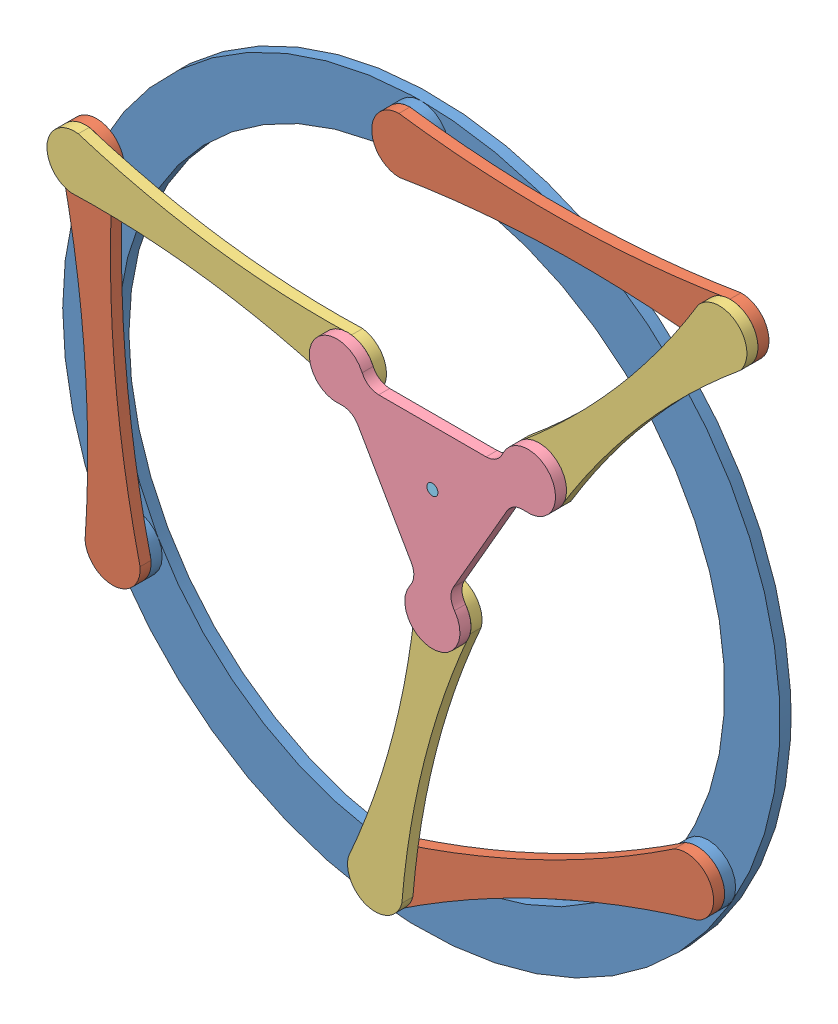
SolidWorks assembly 3RRR, configuration Default. Lengths in mm.
Overall size (660.23 664.5 50).
9 component instances, 5 part files, 21 mates.
Components (placement in the parent):
- Base-1: Base [Default] at origin size (650 650 20)
- Proximal Link-1: Proximal Link [Default] at (-272.0437 -0.4999 20) x (-0.081574 0.996667 0) z (0 0 1) size (350 50 20)
- Proximal Link-2: Proximal Link [Default] at (123.963 -213.6101 20) x (-0.905631 -0.424068 0) z (0 0 1) size (350 50 20)
- Proximal Link-3: Proximal Link [Default] at (149.985 302.119 20) x (0.9999 0.014127 0) z (0 0 1) size (350 50 20)
- Distal Link-1: Distal Link [Default] at (-160.4411 132.0001 30) x (0.990709 -0.136001 0) z (0 0 1) size (300 50 20)
- Distal Link-2: Distal Link [Default] at (19.0592 -156.1101 30) x (0.247526 0.968881 0) z (0 0 1) size (300 50 20)
- Distal Link-3: Distal Link [Default] at (218.2863 209.619 30) x (-0.65347 -0.756952 0) z (0 0 1) size (300 50 20)
- Platform-1: Platform [Default] at (50 65 50) x (-1 0 0) z (0 0 1) size (223.21 200 20)
- Pen-1: Pen [Default] at (50 65 50) x (0.104755 0.994498 0) z (0 0 -1) size (10 10 50)
Mates (geometry in assembly coordinates):
- Coincident5: coordinate: unknown of Base-1
- Concentric1: concentric anti-aligned: cylinder of Base-1 through (-259.8076 -150 20) axis (0 0 -1) radius 16.25; cylinder of Proximal Link-1 through (-259.8076 -150 10) axis (0 0 1) radius 16.25
- Coincident6: coincident anti-aligned: plane of Base-1 through (0 0 10) normal (0 0 1); plane of Proximal Link-1 through (-259.8076 -150 10) normal (0 0 -1)
- Concentric2: concentric anti-aligned: cylinder of Base-1 through (259.8076 -150 20) axis (0 0 -1) radius 16.25; cylinder of Proximal Link-2 through (259.8076 -150 10) axis (0 0 1) radius 16.25
- Coincident7: coincident anti-aligned: plane of Base-1 through (0 0 10) normal (0 0 1); plane of Proximal Link-2 through (259.8076 -150 10) normal (0 0 -1)
- Concentric3: concentric anti-aligned: cylinder of Base-1 through (0 300 20) axis (0 0 -1) radius 16.25; cylinder of Proximal Link-3 through (0 300 10) axis (0 0 1) radius 16.25
- Coincident8: coincident anti-aligned: plane of Base-1 through (0 0 10) normal (0 0 1); plane of Proximal Link-3 through (0 300 10) normal (0 0 -1)
- Concentric4: concentric aligned: cylinder of Proximal Link-1 through (-284.2797 149.0002 20) axis (0 0 1) radius 16.25; cylinder of Distal Link-1 through (-284.2797 149.0002 20) axis (0 0 1) radius 16.25
- Coincident9: coincident anti-aligned: plane of Proximal Link-1 through (-783.3155 32.9051 30) normal (0 0 1); plane of Distal Link-1 through (-46.5349 502.2034 30) normal (0 0 -1)
- Concentric5: concentric aligned: cylinder of Proximal Link-2 through (-11.8816 -277.2203 20) axis (0 0 1) radius 16.25; cylinder of Distal Link-2 through (-11.8816 -277.2203 20) axis (0 0 1) radius 16.25
- Coincident10: coincident anti-aligned: plane of Proximal Link-2 through (270.9764 -704.4277 30) normal (0 0 1); plane of Distal Link-2 through (-335.8301 -0.9369 30) normal (0 0 -1)
- Concentric6: concentric aligned: cylinder of Proximal Link-3 through (299.9701 304.238 20) axis (0 0 1) radius 16.25; cylinder of Distal Link-3 through (299.9701 304.238 20) axis (0 0 1) radius 16.25
- Coincident11: coincident anti-aligned: plane of Proximal Link-3 through (217.8175 809.9709 30) normal (0 0 1); plane of Distal Link-3 through (466.7931 -87.4828 30) normal (0 0 -1)
- Concentric8: concentric aligned: cylinder of Distal Link-1 through (-36.6025 115 30) axis (0 0 1) radius 16.25; cylinder of Platform-1 through (-36.6025 115 30) axis (0 0 1) radius 16.25
- Coincident12: coincident anti-aligned: plane of Distal Link-1 through (-46.5349 502.2034 40) normal (0 0 1); plane of Platform-1 through (16.9699 -10.2901 40) normal (0 0 -1)
- Concentric9: concentric aligned: cylinder of Distal Link-2 through (50 -34.9999 30) axis (0 0 1) radius 16.25; cylinder of Platform-1 through (50 -34.9999 30) axis (0 0 1) radius 16.25
- Concentric10: concentric aligned: cylinder of Distal Link-3 through (136.6025 115 30) axis (0 0 1) radius 16.25; cylinder of Platform-1 through (136.6025 115 30) axis (0 0 1) radius 16.25
- Distance2: distance = 115 mm aligned: plane of Platform-1 through (1.3118 115 40) normal (0 1 0)
- Distance1: distance = 96.0469 mm: point of assembly; point of assembly; point of Platform-1
- Coincident13: coincident aligned: plane of Platform-1 through (16.9699 -10.2901 50) normal (0 0 1); plane of Pen-1 through (50 65 50) normal (0 0 1)
- Concentric11: concentric aligned: cylinder of Platform-1 through (50 65 40) axis (0 0 1) radius 5; cylinder of Pen-1 through (50 65 10) axis (0 0 1) radius 5
